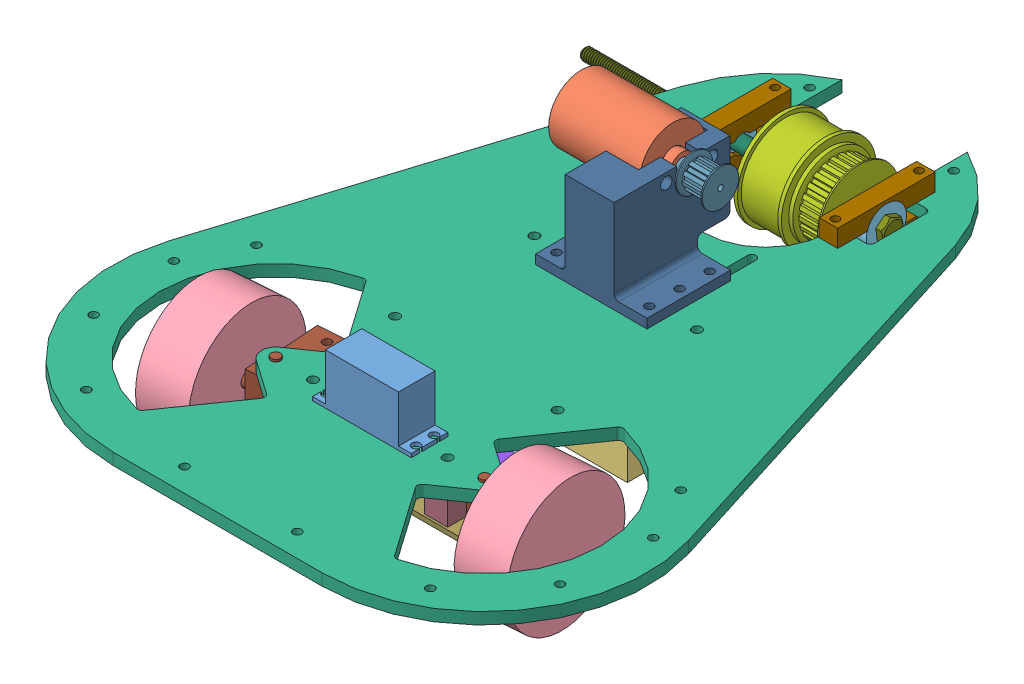
SolidWorks assembly full_Car, configuration Default. Lengths in mm.
Overall size (292.1 134.72 591.82).
27 component instances, 18 part files, 57 mates.
Components (placement in the parent):
- Ref_Sketch-1: Ref_Sketch [Default] at origin size (134.62 20.32 248.92)
- servo-1: servo [Default] at (0 26.13 0) x (-1 0 0) z (0 -1 0) size (54 35.4 44.7)
- motor-1: motor [Default] at (-46.5 62.23 -156.6037) x (0 0.942061 0.335441) z (0 0.335441 -0.942061) size (36 67.5 36)
- battery-1: battery [Default] at (0 -1.84 -90.6608) x (-1 0 0) z (0 0 -1) size (135 24 46)
- wheel-1: wheel [Default] at (85.0087 0 -2.1297) x (-0.053148 -0.716807 -0.695243) z (-0.997091 0 0.076223) size (70 70 27)
- wheel-2: wheel [Default] at (-85.0087 0 2.1297) x (0.069408 0.413309 0.907942) z (-0.997091 0 0.076223) size (70 70 27)
- bearing-1: bearing [Default] at (37.45 13.335 -232.41) x (0 -0.676197 -0.736721) z (0 -0.736721 0.676197) size (22 7 22)
- bearing-2: bearing [Default] at (-44.45 13.335 -232.41) x (0 -1 0) z (0 0 1) size (22 7 22)
- main_frame-1: main_frame [Default] at origin size (292.1 26.67 591.82)
- back_wheel-1: back_wheel [Default] at (19 13.335 -232.41) x (1 0 0) z (0 0.867384 0.497639) size (42.5 52 52)
- steering_linkage_bar-2: steering_linkage_bar [Default] at (-2.3233 11.684 -30.3913) size (134.62 2.54 10.16)
- bearing_block-3: bearing_block [Default] at (-78.74 13.335 0) size (10.16 9.52 53.34)
- motor_mount-1: motor_mount [Default] at (0 16.51 14.0843) size (60.96 50.8 63.5)
- left_upright-1: left_upright [Default] at (0.1663 0 4.3561) x (0.997091 0 -0.076223) z (0.076223 0 0.997091) size (31.75 35.56 42.93)
- steering_retention_bar-1: steering_retention_bar [Default] at origin size (134.62 22.86 256.54)
- left_upright-3: left_upright [right_upright] at (-106.5359 0 3.7753) x (0.997091 0 -0.076223) z (0.076223 0 0.997091) size (31.75 35.56 42.93)
- upright_stand-1: upright_stand [Default] at (-97.79 0 0) size (12.7 20.32 12.7)
- upright_stand-2: upright_stand [Default] at (36.83 0 -60.96) x (0 0 1) z (-1 0 0) size (12.7 20.32 12.7)
- 1428N2_T5 Series Timing Belt Pulley(2)-1: 1428N2_T5 Series Timing Belt Pulley(2) [1428N2] at (19 62.23 -156.6037) x (1 0 0) z (0 0.121957 -0.992535) size (21 20 20)
- bearing_block-6: bearing_block [Default] at (-78.74 13.335 -464.82) x (1 0 0) z (0 0 -1) size (10.16 9.52 53.34)
- rear_axle_spacer-1: rear_axle_spacer [v2] at (-19.05 13.335 -232.41) x (0 1 0) z (0 0 1) size (8 25.4 8)
- rear_axle_spacer-2: rear_axle_spacer [Default] at (44.45 13.335 -232.41) x (0 0.878002 0.478658) z (0 -0.478658 0.878002) size (8 14.95 8)
- 92800A365_18-8 Stainless Steel Hex Head Screw-2: 92800A365_18-8 Stainless Steel Hex Head Screw [92800A365] at (44.45 13.335 -232.41) x (0 0.925796 -0.378024) z (1 0 0) size (11.11 13.98 170.18)
- 93827A211_High-Strength Steel Hex Nut-1: 93827A211_High-Strength Steel Hex Nut [93827A211] at (-47.2281 13.335 -232.41) x (0 -0.922765 0.385364) z (1 0 0) size (11.11 12.83 6.51)
- 93827A211_High-Strength Steel Hex Nut-3: 93827A211_High-Strength Steel Hex Nut [93827A211] at (-15.7781 13.335 -232.41) x (0 -0.97287 -0.231351) z (1 0 0) size (11.11 12.83 6.51)
- bearing_block-7: bearing_block [Default] at (78.74 13.335 -464.82) x (-1 0 0) z (0 0 -1) size (10.16 9.52 53.34)
- bearing_block-8: bearing_block [Default] at (78.74 13.335 0) x (-1 0 0) z (0 0 1) size (10.16 9.52 53.34)
Mates (geometry in assembly coordinates):
- Coincident1: coordinate: point of main_frame-1
- Coincident3: coordinate: unknown of steering_retention_bar-1
- Coincident7: coincident anti-aligned: plane of servo-1 through (0 26.13 0) normal (0 0 -1)
- Coincident9: coordinate: unknown of Ref_Sketch-1
- Coincident14: coincident aligned: plane of motor_mount-1 through (0 16.51 14.0843) normal (1 0 0)
- Concentric3: concentric aligned: cylinder of motor-1 through (3.5 62.23 -156.6037) axis (-1 0 0) radius 18; cylinder of motor_mount-1 through (12.39 62.23 -156.6037) axis (-1 0 0) radius 6.858
- Coincident19: coincident anti-aligned: plane of left_upright-1 through (97.8403 1.524 -9.4791) normal (0 -1 0); plane of steering_linkage_bar-2 through (-2.3233 1.524 -30.3913) normal (0 1 0)
- Coincident21: coincident anti-aligned: plane of motor_mount-1 through (3.5 62.23 -156.6037) normal (-1 0 0); plane of motor-1 through (3.5 62.23 -156.6037) normal (1 0 0)
- Coincident29: coincident anti-aligned: plane of servo-1 through (0 26.13 0) normal (-1 0 0)
- Coincident32: coincident aligned: plane of left_upright-1 through (85.4927 10.16 4.2019) normal (0.997091 0 -0.076223); plane of wheel-1 through (85.0087 0 -2.1297) normal (0.997091 0 -0.076223)
- Coincident41: coincident anti-aligned: plane of main_frame-1 through (0 16.51 0) normal (0 1 0); plane of servo-1 through (0 16.51 0) normal (0 -1 0)
- Concentric17: concentric aligned: cylinder of bearing_block-3 through (-37.45 13.335 -232.41) axis (-1 0 0) radius 11; cylinder of bearing-2 through (-37.45 13.335 -232.41) axis (-1 0 0) radius 11
- Coincident48: coincident aligned: plane of bearing_block-3 through (-44.45 26.035 0) normal (-1 0 0); plane of bearing-2 through (-44.45 13.335 -232.41) normal (-1 0 0)
- Coincident58: coincident anti-aligned: plane of steering_retention_bar-1 through (0 -10.16 0) normal (0 1 0); plane of upright_stand-1 through (-97.79 -10.16 0) normal (0 -1 0)
- Coincident67: coincident anti-aligned: plane of battery-1 through (0 -1.84 -90.6608) normal (-1 0 0)
- Coincident69: coincident anti-aligned: plane of main_frame-1 through (0 10.16 0) normal (0 -1 0); plane of battery-1 through (0 10.16 -90.6608) normal (0 1 0)
- Concentric28: concentric: unknown of ?; cylinder of upright_stand-1 through (-36.83 10.16 0) axis (0 -1 0) radius 2.54
- Concentric29: concentric anti-aligned: cylinder of motor-1 through (21 62.23 -156.6037) axis (-1 0 0) radius 1.5875; cylinder of 1428N2_T5 Series Timing Belt Pulley(2)-1 through (1.7586 62.23 -156.6037) axis (1 0 0) radius 1.5
- Coincident74: coincident aligned: plane of main_frame-1 through (0 0 -232.41) normal (0 0 1); plane of bearing_block-3 through (-78.74 13.335 -232.41) normal (0 0 1)
- Concentric35: concentric anti-aligned: cylinder of bearing-1 through (44.45 13.335 -232.41) axis (-1 0 0) radius 4; circle of 92800A365_18-8 Stainless Steel Hex Head Screw-2
- Concentric37: concentric anti-aligned: circle of 92800A365_18-8 Stainless Steel Hex Head Screw-2; circle of 93827A211_High-Strength Steel Hex Nut-1
- Concentric39: concentric aligned: circle of 93827A211_High-Strength Steel Hex Nut-1; circle of 93827A211_High-Strength Steel Hex Nut-3
- Coincident86: coincident anti-aligned: plane of bearing_block-3 through (-44.45 26.035 0) normal (-1 0 0); plane of 93827A211_High-Strength Steel Hex Nut-1 through (-44.45 17.2259 -237.5113) normal (1 0 0)
- Concentric44: concentric: unknown of ?; cylinder of upright_stand-2 through (36.83 10.16 0) axis (0 -1 0) radius 2.54
- Coincident90: coincident anti-aligned: plane of main_frame-1 through (0 10.16 0) normal (0 -1 0); plane of upright_stand-2 through (36.83 10.16 -60.96) normal (0 1 0)
- Coincident91: coincident aligned: plane of upright_stand-1 through (-43.18 10.16 6.35) normal (0 0 1); plane of upright_stand-2 through (30.48 10.16 6.35) normal (0 0 1)
- Coincident92: coincident anti-aligned: plane of wheel-2 through (-85.0087 0 2.1297) normal (0.997091 0 -0.076223); plane of left_upright-3 through (-84.5247 10.16 8.4612) normal (-0.997091 0 0.076223)
- Concentric46: concentric aligned: cylinder of bearing-1 through (44.45 13.335 -232.41) axis (-1 0 0) radius 4; cylinder of bearing-2 through (-37.45 13.335 -232.41) axis (-1 0 0) radius 4
- Coincident96: coincident anti-aligned: plane of battery-1 through (0 -1.84 -90.6608) normal (0 0 -1); plane of main_frame-1 through (0 0 -90.6608) normal (0 0 1)
- Concentric47: concentric aligned: cylinder of steering_linkage_bar-2 through (54.8267 -1.016 -30.3913) axis (0 1 0) radius 2.286; cylinder of left_upright-1 through (54.8267 -17.78 -30.3913) axis (0 1 0) radius 2.286
- Concentric48: concentric anti-aligned: cylinder of wheel-1 through (71.548 0 -1.1007) axis (0.997091 0 -0.076223) radius 35; cylinder of left_upright-1 through (113.4819 0 -4.3063) axis (-0.997091 0 0.076223) radius 3.81
- Concentric49: concentric aligned: cylinder of wheel-2 through (-98.4694 0 3.1587) axis (0.997091 0 -0.076223) radius 35; cylinder of left_upright-3 through (-113.4819 0 4.3063) axis (0.997091 0 -0.076223) radius 3.81
- Concentric50: concentric anti-aligned: cylinder of bearing-2 through (-37.45 13.335 -232.41) axis (-1 0 0) radius 11; cylinder of rear_axle_spacer-1 through (-44.45 13.335 -232.41) axis (1 0 0) radius 3.175
- Coincident97: coincident anti-aligned: plane of 93827A211_High-Strength Steel Hex Nut-1 through (-44.45 17.2259 -237.5113) normal (1 0 0); plane of rear_axle_spacer-1 through (-44.45 13.335 -232.41) normal (-1 0 0)
- Concentric51: concentric aligned: cylinder of rear_axle_spacer-1 through (-44.45 13.335 -232.41) axis (1 0 0) radius 4; cylinder of rear_axle_spacer-2 through (29.502 13.335 -232.41) axis (1 0 0) radius 4
- Coincident99: coincident anti-aligned: plane of 92800A365_18-8 Stainless Steel Hex Head Screw-2 through (44.45 8.4482 -230.4146) normal (-1 0 0); plane of rear_axle_spacer-2 through (44.45 13.335 -232.41) normal (1 0 0)
- Coincident100: coincident aligned: plane of motor_mount-1 through (0 16.51 14.0843) normal (1 0 0)
- Coincident101: coincident anti-aligned: plane of main_frame-1 through (0 16.51 0) normal (0 1 0); plane of motor_mount-1 through (0 16.51 14.0843) normal (0 -1 0)
- Concentric52: concentric aligned: cylinder of bearing-2 through (-37.45 13.335 -232.41) axis (-1 0 0) radius 11; cylinder of back_wheel-1 through (8.5 13.335 -232.41) axis (-1 0 0) radius 22
- Coincident103: coincident aligned: plane of back_wheel-1 through (0 13.335 -232.41) normal (1 0 0)
- Coincident105: coincident anti-aligned: plane of motor-1 through (8.5 62.23 -156.6037) normal (1 0 0); plane of 1428N2_T5 Series Timing Belt Pulley(2)-1 through (8.5 60.2449 -156.8476) normal (-1 0 0)
- Coincident106: coincident anti-aligned: plane of back_wheel-1 through (-13 13.335 -232.41) normal (-1 0 0); plane of 93827A211_High-Strength Steel Hex Nut-3 through (-13 19.4827 -234.2454) normal (1 0 0)
- Concentric53: concentric aligned: cylinder of main_frame-1 through (57.15 10.16 0) axis (0 -1 0) radius 2.54; cylinder of left_upright-1 through (57.15 32.5842 0) axis (0 -1 0) radius 2.54
- Coincident107: coincident anti-aligned: plane of main_frame-1 through (0 10.16 0) normal (0 -1 0); plane of left_upright-1 through (0.1663 10.16 4.3561) normal (0 1 0)
- Concentric54: concentric aligned: cylinder of main_frame-1 through (-57.15 10.16 0) axis (0 -1 0) radius 2.54; cylinder of left_upright-3 through (-57.15 32.5842 0) axis (0 -1 0) radius 2.54
- Coincident108: coincident anti-aligned: plane of main_frame-1 through (0 10.16 0) normal (0 -1 0); plane of left_upright-3 through (-106.5359 10.16 3.7753) normal (0 1 0)
- Concentric55: concentric aligned: cylinder of steering_linkage_bar-2 through (-59.4733 -1.016 -30.3913) axis (0 1 0) radius 2.286; cylinder of left_upright-3 through (-59.4733 -17.78 -30.3913) axis (0 1 0) radius 2.286
- Coincident111: coincident aligned: plane of main_frame-1 through (-34.29 10.16 -248.92) normal (1 0 0); plane of bearing_block-3 through (-34.29 26.035 0) normal (1 0 0)
- Coincident112: coincident anti-aligned: plane of main_frame-1 through (0 10.16 0) normal (0 -1 0); plane of bearing_block-6 through (-78.74 10.16 -464.82) normal (0 1 0)
- Coincident113: coincident aligned: plane of bearing_block-3 through (-34.29 26.035 0) normal (1 0 0); plane of bearing_block-6 through (-34.29 0.635 -464.82) normal (1 0 0)
- Coincident115: coincident aligned: plane of bearing_block-3 through (-78.74 26.035 -259.08) normal (0 0 -1); plane of bearing_block-6 through (-78.74 0.635 -259.08) normal (0 0 -1)
- Coincident116: coincident aligned: plane of bearing_block-7 through (34.29 26.035 -464.82) normal (-1 0 0); plane of bearing_block-8 through (34.29 0.635 0) normal (-1 0 0)
- Coincident117: coincident aligned: plane of bearing_block-7 through (78.74 26.035 -259.08) normal (0 0 -1); plane of bearing_block-8 through (78.74 0.635 -259.08) normal (0 0 -1)
- Coincident118: coincident aligned: plane of bearing_block-3 through (-78.74 26.035 -259.08) normal (0 0 -1); plane of bearing_block-7 through (78.74 26.035 -259.08) normal (0 0 -1)
- Coincident120: coincident anti-aligned: plane of main_frame-1 through (0 10.16 0) normal (0 -1 0); plane of bearing_block-8 through (78.74 10.16 0) normal (0 1 0)
- Coincident121: coincident aligned: plane of main_frame-1 through (34.29 10.16 -502.92) normal (-1 0 0); plane of bearing_block-7 through (34.29 26.035 -464.82) normal (-1 0 0)
- Concentric56: concentric aligned: cylinder of bearing-2 through (-37.45 13.335 -232.41) axis (-1 0 0) radius 11; cylinder of bearing_block-6 through (-37.45 13.335 -232.41) axis (-1 0 0) radius 11
